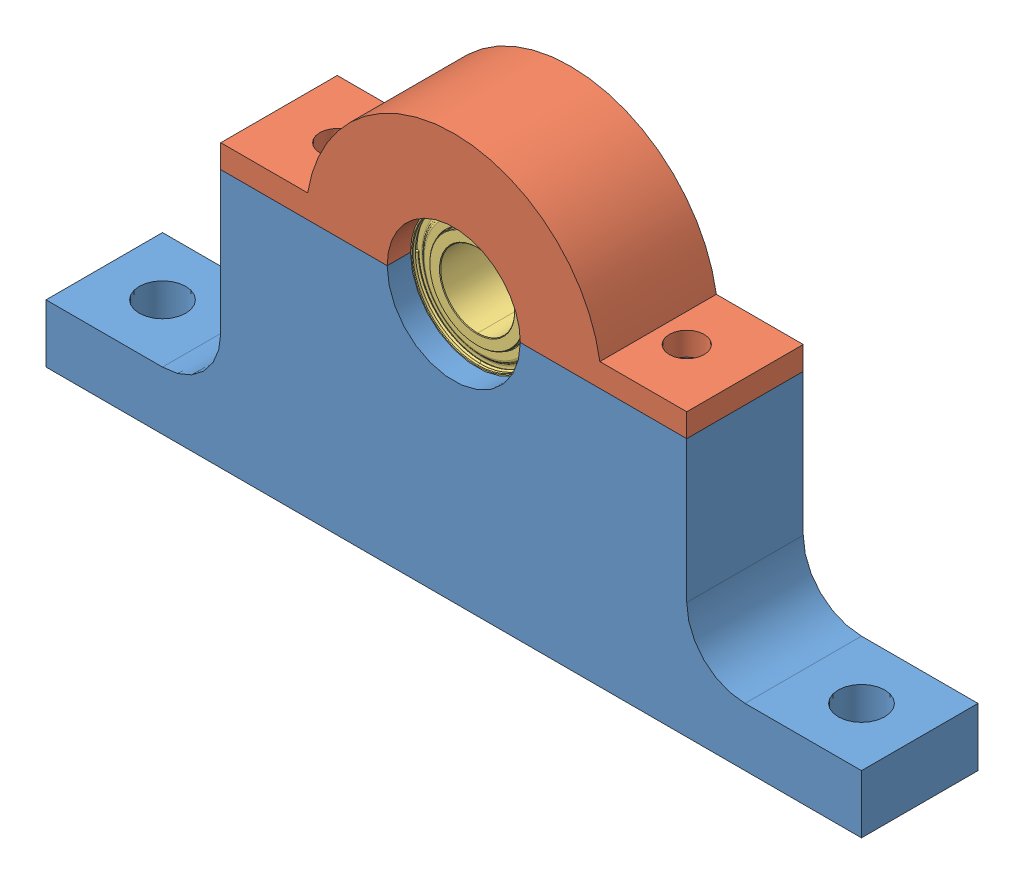
SolidWorks assembly bearing_mount_assem, configuration Default. Lengths in mm.
Overall size (70 34.88 10).
3 component instances, 3 part files, 8 mates.
Components (placement in the parent):
- short_bearing_mount-1: short_bearing_mount [Default] at origin size (70 22.18 10)
- top_bearing_mount-1: top_bearing_mount [Default] at (0 22.1798 0) x (1 0 0) z (0 -1 0) size (40 10 12.7)
- 1600-0002-0250.step-1: 1600-0002-0250.step [Default] at (0 22.1798 0.6188) x (1 0 0) z (0 1 0) size (12.7 4.76 12.7)
Mates (geometry in assembly coordinates):
- Coincident1: coincident aligned: plane of short_bearing_mount-1 through (0 0 0) normal (0 0 1)
- Coincident2: coincident aligned: plane of short_bearing_mount-1 through (0 0 0) normal (0 1 0)
- Coincident3: coincident aligned: plane of short_bearing_mount-1 through (0 0 0) normal (1 0 0)
- Concentric1: concentric anti-aligned: cylinder of short_bearing_mount-1 through (0 22.1798 3) axis (0 0 -1) radius 6.985; cylinder of 1600-0002-0250.step-1 through (0 22.1798 -1.7625) axis (0 0 1) radius 3.175
- Coincident4: coincident: plane of short_bearing_mount-1 through (0 22.1798 3) normal (0 0 -1); plane of 1600-0002-0250.step-1 through (0 22.1798 3) normal (0 0 1)
- Coincident5: coincident anti-aligned: plane of short_bearing_mount-1 through (0 22.1798 0) normal (0 1 0); plane of top_bearing_mount-1 through (0 22.1798 5) normal (0 -1 0)
- Concentric2: concentric anti-aligned: cylinder of short_bearing_mount-1 through (-15 15.1798 0) axis (0 1 0) radius 1.5; cylinder of top_bearing_mount-1 through (-15 24.1798 0) axis (0 -1 0) radius 1.5
- Concentric3: concentric anti-aligned: cylinder of short_bearing_mount-1 through (15 15.1798 0) axis (0 1 0) radius 1.5; cylinder of top_bearing_mount-1 through (15 24.1798 0) axis (0 -1 0) radius 1.5
